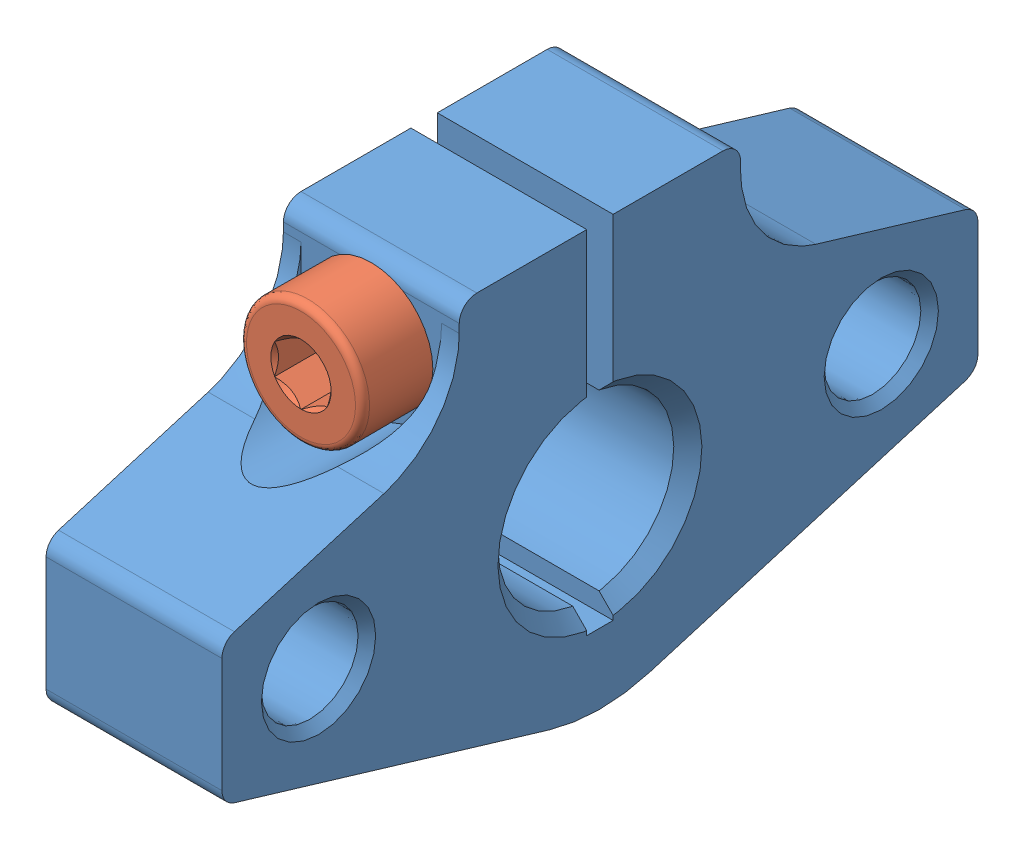
SolidWorks assembly B17C-SHFMQ10, configuration Default. Lengths in mm.
Overall size (10.01 24 43).
2 component instances, 2 part files, 0 mates.
Components (placement in the parent):
- C-SHFMQ10_b-1: C-SHFMQ10_b [Default] at origin size (10.01 24 43)
- Slotted head cap screw ISO 4762 - M4x16-1: Slotted head cap screw ISO 4762 - M4x16 [Default] at (5 10 8) x (0 0 -1) z (-1 0 0) size (20.01 7 7)
